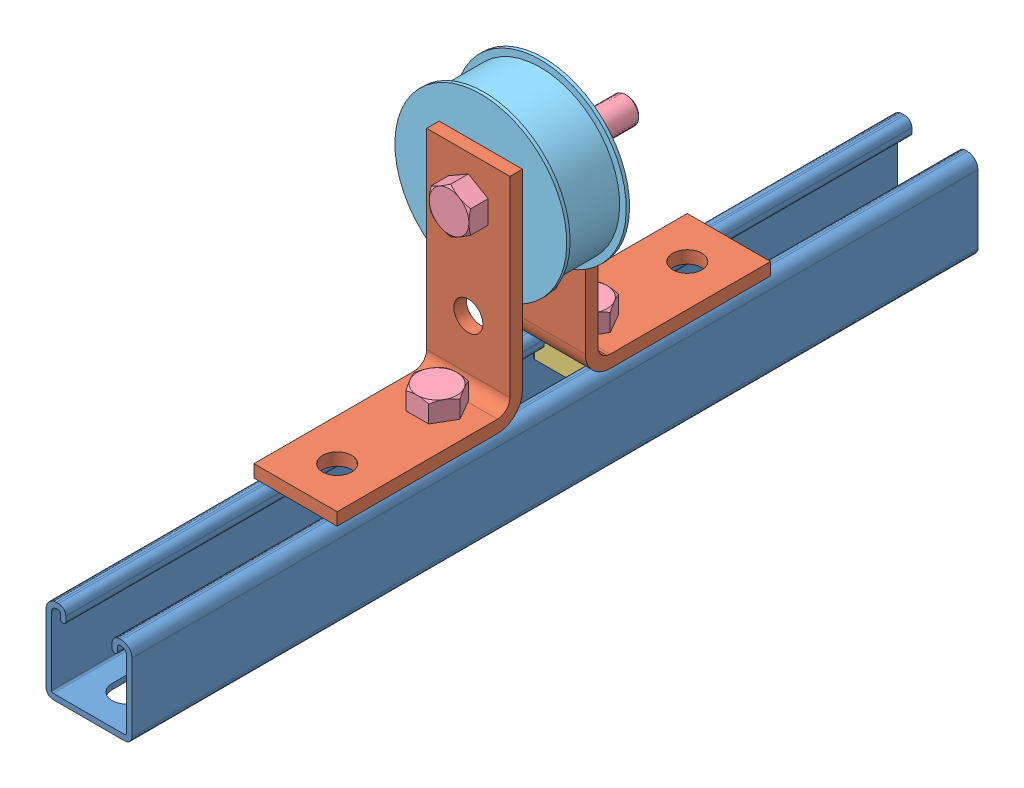
SolidWorks assembly Lower Inner Pulley System, configuration Default. Lengths in mm.
Overall size (104.89 177.72 406.4).
12 component instances, 6 part files, 21 mates.
Components (placement in the parent):
- P1000T - Unistrut Channel (Slots)-1: P1000T - Unistrut Channel (Slots) [1'-4"] at (182.1547 309.6757 710.0018) size (41.28 41.27 406.4)
- P1325 - Unistrut 4-Hole 90 deg Fitting-1: P1325 - Unistrut 4-Hole 90 deg Fitting [Default] at (202.2645 434.3132 521.883) x (0 0 1) z (1 0 0) size (89 104 40)
- P1325 - Unistrut 4-Hole 90 deg Fitting-2: P1325 - Unistrut 4-Hole 90 deg Fitting [Default] at (162.2645 434.3132 491.7205) x (0 0 -1) z (-1 0 0) size (89 104 40)
- Channel Nut-1: Channel Nut [P2223] at (182.2645 325.9538 542.883) x (1 0 0) z (0 1 0) size (34.99 19.63 34.65)
  - P3013 - Channel Nut-3: P3013 - Channel Nut [.5"] at origin size (34.99 19.63 9.53)
  - hex bolt_ai-1: hex bolt_ai [HBOLT 0.5000-13x1x1-N] at (0 0 19.555) x (0 0 -1) z (0 -1 0) size (34.65 22 19.05)
- Channel Nut-2: Channel Nut [P2223] at (182.2645 325.9538 470.7205) x (1 0 0) z (0 1 0) size (34.99 19.63 34.65)
  - P3013 - Channel Nut-3: P3013 - Channel Nut [.5"] at origin size (34.99 19.63 9.53)
  - hex bolt_ai-1: hex bolt_ai [HBOLT 0.5000-13x1x1-N] at (0 0 19.555) x (0 0 -1) z (0 -1 0) size (34.65 22 19.05)
- Wide Pulley-1: Wide Pulley [3"x0.5"] at (182.2645 414.3132 506.8018) x (0.945754 0.324885 0) z (0 0 1) size (82.55 82.55 30.16)
- hex bolt_ai-1: hex bolt_ai [HBOLT 0.5000-20x3x3-N] at (182.2645 414.3132 537.1286) x (0 0 -1) z (0.5 -0.866025 0) size (85.45 22 19.05)
- hex nut_ai-1: hex nut_ai [HNUT 0.5000-20-D-N] at (182.2645 414.3132 485.7205) size (19.05 22 11.38)
Mates (geometry in assembly coordinates):
- Coincident1: coincident anti-aligned: plane of P1000T - Unistrut Channel (Slots)-1 through (193.2674 324.5092 303.6018) normal (-1 0 0); plane of Channel Nut-1/P3013 - Channel Nut-3 through (193.2674 324.2244 552.409) normal (1 0 0)
- Tangent2: tangent anti-aligned: cylinder of P1000T - Unistrut Channel (Slots)-1 through (194.6009 324.5092 303.6018) axis (0 0 1) radius 1.3335; plane of Channel Nut-1/P3013 - Channel Nut-3 through (195.6376 323.1757 552.409) normal (0 1 0)
- Coincident2: coincident anti-aligned: plane of P1000T - Unistrut Channel (Slots)-1 through (193.2674 324.5092 303.6018) normal (-1 0 0); plane of Channel Nut-2/P3013 - Channel Nut-3 through (193.2674 324.2244 480.2465) normal (1 0 0)
- Tangent3: tangent anti-aligned: cylinder of P1000T - Unistrut Channel (Slots)-1 through (194.6009 324.5092 303.6018) axis (0 0 1) radius 1.3335; plane of Channel Nut-2/P3013 - Channel Nut-3 through (195.6376 323.1757 480.2465) normal (0 1 0)
- Coincident3: coincident anti-aligned: plane of P1000T - Unistrut Channel (Slots)-1 through (196.7282 330.3132 303.6018) normal (0 1 0); plane of P1325 - Unistrut 4-Hole 90 deg Fitting-1 through (162.2645 330.3132 610.883) normal (0 -1 0)
- Concentric2: concentric aligned: cylinder of P1325 - Unistrut 4-Hole 90 deg Fitting-1 through (182.2645 336.3132 542.883) axis (0 1 0) radius 7; cylinder of Channel Nut-1/hex bolt_ai-1 through (182.2645 345.5088 542.883) axis (0 1 0) radius 6.35
- Parallel2: parallel aligned: plane of P1000T - Unistrut Channel (Slots)-1 through (202.7924 325.2649 303.6018) normal (1 0 0); plane of P1325 - Unistrut 4-Hole 90 deg Fitting-1 through (202.2645 434.3132 521.883) normal (1 0 0)
- Coincident5: coincident anti-aligned: plane of P1000T - Unistrut Channel (Slots)-1 through (196.7282 330.3132 303.6018) normal (0 1 0); plane of P1325 - Unistrut 4-Hole 90 deg Fitting-2 through (202.2645 330.3132 402.7205) normal (0 -1 0)
- Concentric3: concentric aligned: cylinder of P1325 - Unistrut 4-Hole 90 deg Fitting-2 through (182.2645 336.3132 470.7205) axis (0 1 0) radius 7; cylinder of Channel Nut-2/hex bolt_ai-1 through (182.2645 345.5088 470.7205) axis (0 1 0) radius 6.35
- Parallel3: parallel aligned: plane of P1000T - Unistrut Channel (Slots)-1 through (202.7924 325.2649 303.6018) normal (1 0 0); plane of P1325 - Unistrut 4-Hole 90 deg Fitting-2 through (202.2645 434.3132 491.7205) normal (1 0 0)
- Concentric4: concentric anti-aligned: cylinder of P1325 - Unistrut 4-Hole 90 deg Fitting-1 through (182.2645 414.3132 521.883) axis (0 0 -1) radius 7; cylinder of hex bolt_ai-1 through (182.2645 414.3132 537.1286) axis (0 0 1) radius 6.35
- Concentric5: concentric aligned: cylinder of Wide Pulley-1 through (182.2645 414.3132 491.7205) axis (0 0 1) radius 6.35; cylinder of hex bolt_ai-1 through (182.2645 414.3132 537.1286) axis (0 0 1) radius 6.35
- Concentric6: concentric aligned: cylinder of P1325 - Unistrut 4-Hole 90 deg Fitting-2 through (182.2645 414.3132 491.7205) axis (0 0 1) radius 7; cylinder of hex bolt_ai-1 through (182.2645 414.3132 537.1286) axis (0 0 1) radius 6.35
- Parallel4: parallel aligned: plane of P1325 - Unistrut 4-Hole 90 deg Fitting-1 through (202.2645 434.3132 521.883) normal (1 0 0); plane of hex bolt_ai-1 through (191.7895 419.8124 527.883) normal (1 0 0)
- Coincident8: coincident anti-aligned: plane of P1325 - Unistrut 4-Hole 90 deg Fitting-1 through (202.2645 434.3132 527.883) normal (0 0 1); plane of hex bolt_ai-1 through (191.7895 419.8124 527.883) normal (0 0 -1)
- Coincident9: coincident anti-aligned: plane of P1325 - Unistrut 4-Hole 90 deg Fitting-1 through (162.2645 330.3132 521.883) normal (0 0 -1); plane of Wide Pulley-1 through (182.2645 414.3132 521.883) normal (0 0 1)
- Coincident10: coincident anti-aligned: plane of P1325 - Unistrut 4-Hole 90 deg Fitting-2 through (202.2645 330.3132 491.7205) normal (0 0 1); plane of Wide Pulley-1 through (182.2645 414.3132 491.7205) normal (0 0 -1)
- Parallel5: parallel aligned: plane of hex bolt_ai-1 through (191.7895 419.8124 527.883) normal (1 0 0); plane of hex nut_ai-1 through (191.7895 419.8124 474.3413) normal (1 0 0)
- Concentric7: concentric aligned: cylinder of hex bolt_ai-1 through (182.2645 414.3132 537.1286) axis (0 0 1) radius 6.35; cylinder of hex nut_ai-1 through (182.2645 414.3132 474.3413) axis (0 0 1) radius 5.7544
- Coincident12: coincident anti-aligned: plane of P1325 - Unistrut 4-Hole 90 deg Fitting-2 through (162.2645 434.3132 485.7205) normal (0 0 -1); plane of hex nut_ai-1 through (182.2645 425.3117 485.7205) normal (0 0 1)
- Symmetric1: symmetric aligned: plane of Wide Pulley-1 through (182.2645 414.3132 521.883) normal (0 0 1); plane of Wide Pulley-1 through (182.2645 414.3132 491.7205) normal (0 0 -1); plane of assembly through (0 0 506.8018) normal (0 0 1)
